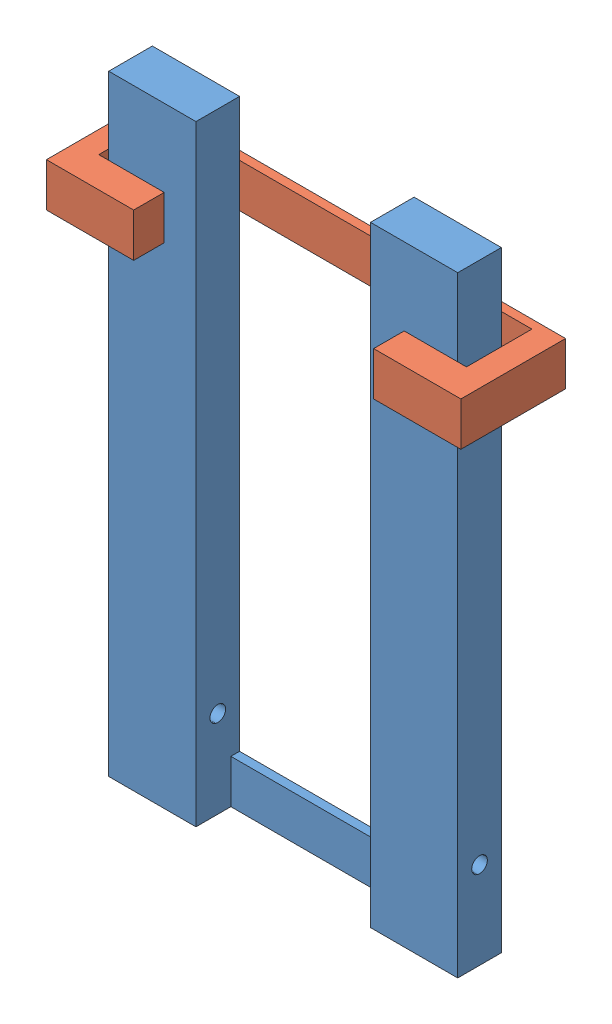
SolidWorks assembly assem2, configuration Default. Lengths in mm.
Overall size (19 28 4.8).
2 component instances, 2 part files, 2 mates.
Components (placement in the parent):
- fork2-1: fork2 [Default] at (-63.2534 14.2138 12.5854) size (16 28 2)
- slider2-1: slider2 [Default] at (-64.709 38.674 11.1854) x (1 0 0) z (0 -1 0) size (19 4.8 2)
Mates (geometry in assembly coordinates):
- Coincident3: coincident anti-aligned: plane of fork2-1 through (-63.2534 14.2138 14.5854) normal (0 0 1); plane of slider2-1 through (-49.709 36.674 14.5854) normal (0 0 -1)
- Distance1: distance = 0.4 mm anti-aligned: plane of slider2-1 through (-46.8534 36.674 14.5854) normal (-1 0 0); plane of fork2-1 through (-47.2534 14.2138 12.9854) normal (1 0 0)
